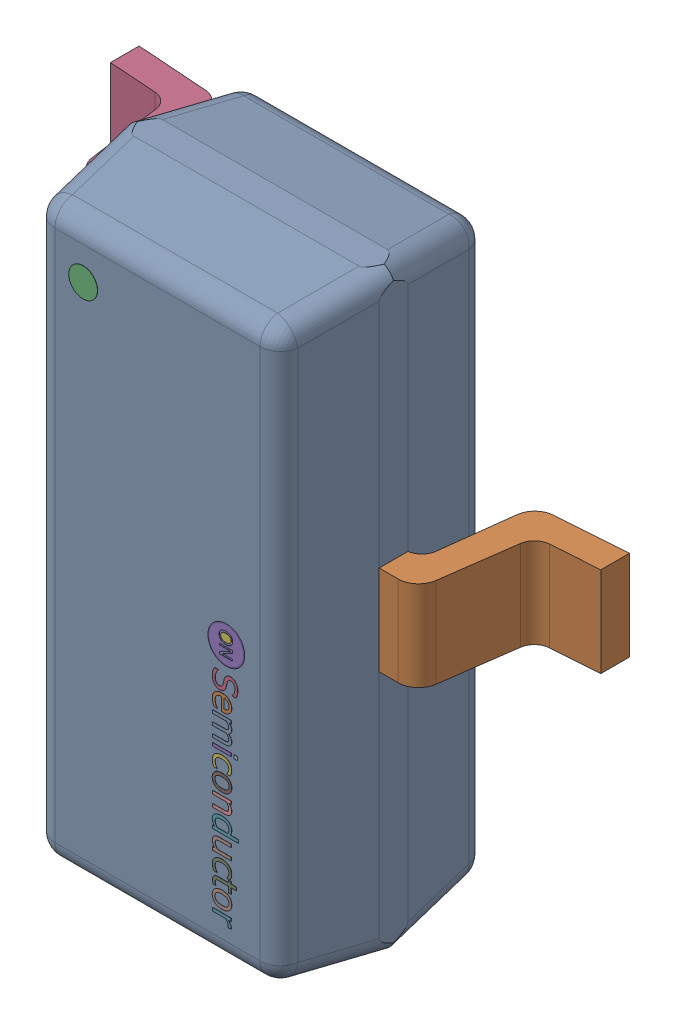
SolidWorks assembly Q4.step, configuration Default. Lengths in mm.
Overall size (2.4 2.9 1.11).
5 component instances, 4 part files, 0 mates.
Components (placement in the parent):
- IC_ON_Semiconductor_NUD3112LT1G_eec.step-1: IC_ON_Semiconductor_NUD3112LT1G_eec.step [Default] at (17.919 10.287 0) x (1 0 0) z (0 0 1) size (2.4 2.9 1.11)
  - 1-5.step-1: 1-5.step [Default] at (0 0 0.1) x (0 1 0) z (0 0 1) size (2.9 1.3 1.01)
  - 2-6.step-1: 2-6.step [Default] x (-1 0 0) z (0 1 0) size (2.4 0.68 2.34)
  - ON Semi Logo - withoutPN.step-1: ON Semi Logo - withoutPN.step [Default] at (-0.2581 -0.9018 1.011) x (-1 0 0) z (0 0 1) size (0.19 0.19 0.1)
  - ON Semi Logo - withoutPN - Copy.step-1: ON Semi Logo - withoutPN - Copy.step [Default] at (-0.2645 -0.8914 1.011) x (-1 0 0) z (0 0 1) size (0.83 2.45 0.1)
